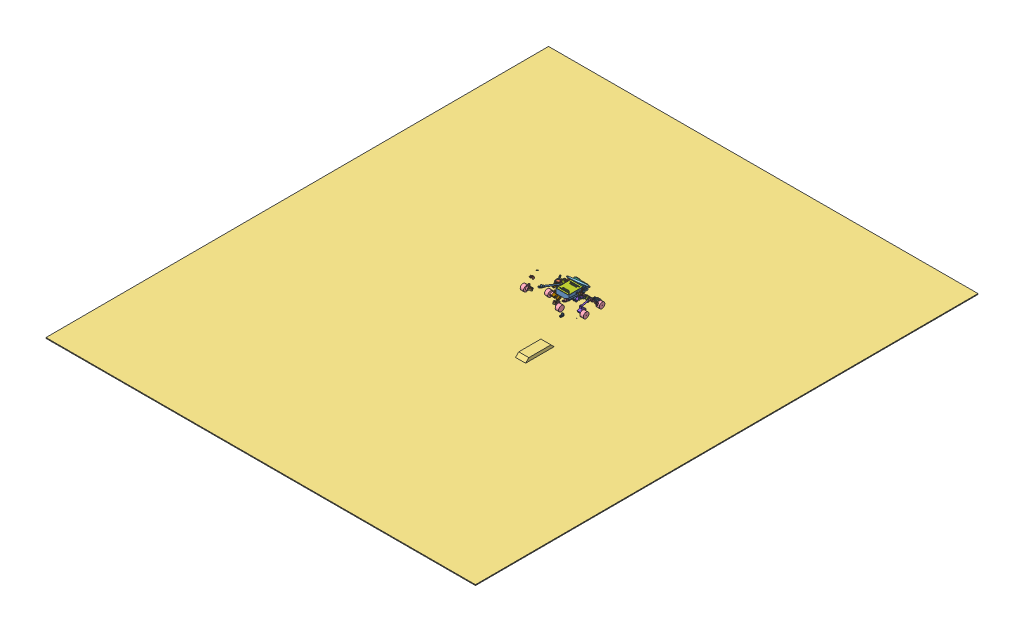
SolidWorks assembly Radius Test, configuration Default. Lengths in mm.
Overall size (5322.83 3059.19 6245.29).
49 component instances, 26 part files, 175 mates.
Components (placement in the parent):
- Electrical Box-1: Electrical Box [Default] at (-2118.9186 210.8039 -599.3636) x (0.999999 0 -0.001669) z (0.001669 0 0.999999) size (183 67.1 235)
- ROCKER JOINT LEFT VF-1: ROCKER JOINT LEFT VF [Default] at (-2135.147 239.3039 -565.7499) x (-0.001463 -0.481199 -0.87661) z (0.999999 0 -0.001669) size (91.82 74.92 47.81)
- ROCKER JOINT RIGHT-1: ROCKER JOINT RIGHT [Default] at (-2288.1468 239.3039 -565.4945) x (-0.001463 -0.481199 -0.87661) z (0.999999 0 -0.001669) size (91.82 74.92 46.81)
- Angled Motor-1: Angled Motor [Default] at (-2300.1865 333.2946 -193.9376) x (0.001463 0.481199 0.87661) z (0.000803 -0.876611 0.481199) size (22.4 36.6 70.6)
- Angled Motor-2: Angled Motor [Default] at (-2296.3187 99.9659 -773.6498) x (-0.329165 0.462199 0.823421) z (-0.86944 0.191867 -0.455259) size (22.4 36.6 70.6)
- Angled Motor-3: Angled Motor [Default] at (-1954.5271 93.2332 -721.9243) x (-0.020357 -0.06226 -0.997852) z (0.000104 -0.998059 0.062271) size (22.4 36.6 70.6)
- Angled Motor-4: Angled Motor [Default] at (-2314.8357 109.8126 -508.2919) x (-0.022203 -0.905756 -0.423217) z (-0.066951 -0.421024 0.904575) size (22.4 36.6 70.6)
- Angled Motor-5: Angled Motor [Default] at (-1934.096 105.6712 -504.4021) x (0.000717 0.90309 0.42945) z (0.001508 -0.429451 0.903089) size (22.4 36.6 70.6)
- Angled Motor-6: Angled Motor [Default] at (-1934.4209 330.8348 -199.0292) x (-0.001463 -0.481199 -0.87661) z (0.000803 -0.876611 0.481199) size (22.4 36.6 70.6)
- Bogie Pivot LEFT VF_LATEST__EVENING-1: Bogie Pivot LEFT VF_LATEST__EVENING [Default] at (-1997.0713 159.9866 -520.5028) x (-0.001666 -0.062271 -0.998058) z (0.999999 0 -0.001669) size (249.12 118.53 110.7)
- Bogie Pivot RIGHT VF_LATEST__EVENING - -1: Bogie Pivot RIGHT VF_LATEST__EVENING -  [Default] at (-2194.7174 158.3806 -518.4135) x (0.048176 -0.063499 -0.996818) z (0.997509 -0.048419 0.051294) size (249.12 118.53 161.7)
- Bogie Pivot joint VFINAL-1: Bogie Pivot joint VFINAL [Default] at (-1997.0839 210.2606 -528.0634) x (-0.001463 -0.481199 -0.87661) z (0.999999 0 -0.001669) size (160.51 100.01 61)
- Bogie - Motor mount-1: Bogie - Motor mount [Default] at (-1997.4723 161.6666 -522.5101) x (-0.001663 -0.083925 -0.996471) z (0.999999 0 -0.001669) size (251.14 245.94 117.56)
- Bogie - Motor mount - RIGHT VF-1: Bogie - Motor mount - RIGHT VF [Default] at (-2281.8294 164.2934 -524.9057) x (0.047046 -0.085126 -0.995259) z (0.997509 -0.048419 0.051294) size (251.14 245.94 117.56)
- Bogie Servo mount-1: Bogie Servo mount [Default] at (-2020.12 159.7927 -520.3812) x (-0.001666 -0.062271 -0.998058) z (0.999999 0 -0.001669) size (471.83 118.53 111.2)
- Servo_Connector_1-2: Servo_Connector_1 [Default] at (-1945.5813 363.9049 -198.0146) x (0.548168 0.402845 0.732958) z (-0.836368 0.263189 0.480854) size (40 15 40)
- Rocker Motor mount vP-2: Rocker Motor mount vP [Default] at (-1961.2668 355.4452 -196.7746) x (0.548168 0.402845 0.732958) z (-0.836368 0.263189 0.480854) size (41.99 25.29 45.95)
- ROCKER SERVO JOINT VF LEFT-1: ROCKER SERVO JOINT VF LEFT [Default] at (-1999.1852 209.1241 -533.8147) x (0.089349 -0.479211 -0.87314) z (0.996 0.043696 0.077939) size (472.67 119.9 110.7)
- ROCKER SERVO JOINT VF RIGHT-1: ROCKER SERVO JOINT VF RIGHT [Default] at (-2277.9099 209.1241 -533.3494) x (0.089349 -0.479211 -0.87314) z (0.996 0.043696 0.077939) size (474.67 119.9 110.7)
- SG90 - Micro Servo 9g - Tower Pro.4-1: SG90 - Micro Servo 9g - Tower Pro.4 [Peça] at (-2285.6539 67.6383 -751.6519) x (-0.332575 0.454133 0.826533) z (-0.365333 -0.870029 0.331032) size (34.5 3.8 16.7)
- SG90 - Micro Servo 9g - Tower Pro.4-2: SG90 - Micro Servo 9g - Tower Pro.4 [Peça] at (-2267.5431 503.5862 -287.7932) x (0.001463 0.481199 0.87661) z (0.999999 0 -0.001669) size (34.5 3.8 16.7)
- M5 BALL-1: M5 BALL [Default] at (-2003.1859 281.6004 -589.1881) x (0.000011 -0.999976 0.006877) z (0.001669 0.006877 0.999975) size (28.4 25.6 8)
- M5 BALL-2: M5 BALL [Default] at (-2236.1856 281.6004 -588.7991) x (-0.000275 0.986308 -0.164916) z (0.001646 0.164916 0.986306) size (28.4 25.6 8)
- SG90 - Micro Servo 9g - Tower Pro.4-5: SG90 - Micro Servo 9g - Tower Pro.4 [Peça] at (-1987.3147 94.1808 -721.0311) x (-0.020357 -0.06226 -0.997852) z (-0.999793 0.001164 0.020324) size (34.5 3.8 16.7)
- SG90 - Micro Servo 9g - Tower Pro.4-6: SG90 - Micro Servo 9g - Tower Pro.4 [Peça] at (-1967.3786 503.5413 -293.4557) x (-0.001463 -0.481199 -0.87661) z (-0.999999 0 0.001669) size (34.5 3.8 16.7)
- Servo_Connector_1-5: Servo_Connector_1 [Default] at (-2269.6339 78.3895 -771.0803) x (0.478238 0.095671 -0.873004) z (-0.123945 -0.976747 -0.174938) size (40 15 40)
- Rocker Motor mount vP-4: Rocker Motor mount vP [Default] at (-1981.0927 114.593 -708.9057) x (0.563873 0.051485 0.824255) z (-0.825861 0.035027 0.562784) size (41.99 25.29 45.95)
- Servo_Connector_1-6: Servo_Connector_1 [Default] at (-1965.3481 122.7464 -706.7224) x (0.563873 0.051485 0.824255) z (-0.825861 0.035027 0.562784) size (40 15 40)
- Rocker Motor mount vP-5: Rocker Motor mount vP [Default] at (-2273.3736 344.6435 -215.9314) x (-0.548168 -0.402845 -0.732958) z (0.836368 -0.263189 -0.480854) size (41.99 25.29 45.95)
- Servo_Connector_1-7: Servo_Connector_1 [Default] at (-2289.0719 350.2095 -222.3906) x (-0.548168 -0.402845 -0.732958) z (0.836368 -0.263189 -0.480854) size (40 15 40)
- Rocker P to Bogie P-1: Rocker P to Bogie P [Default] at (-2014.7332 189.2651 -617.4865) x (-0.818562 -0.386919 0.424559) z (0.001126 0.738029 0.674768) size (14.05 15.92 38.63)
- Rocker P to Bogie P-2: Rocker P to Bogie P [Default] at (-2224.7329 189.2651 -617.1359) x (0.85767 0.346253 -0.380146) z (0.001126 0.738029 0.674768) size (14.05 15.92 38.63)
- Bogie Pivot joint VFINAL-3: Bogie Pivot joint VFINAL [Default] at (-2238.4469 280.9931 -605.0242) x (-0.023795 -0.915549 -0.401503) z (-0.997509 0.048419 -0.051294) size (160.51 100.01 61)
- Bogie P to Servo M-1: Bogie P to Servo M [Default] at (-2270.4158 162.4518 -660.3391) x (0.029002 -0.381348 -0.923976) z (0.396853 -0.843999 0.360796) size (40.99 16.26 14.42)
- Bogie P to Servo M-2: Bogie P to Servo M [Default] at (-1967.3088 159.4533 -658.088) x (-0.001544 -0.380589 -0.924743) z (-0.779236 -0.579106 0.239639) size (40.99 16.26 14.42)
- R to R arm-1: R to R arm [Default] at (-2010.5512 250.7741 -535.4302) x (0.20383 0.254717 0.94529) z (-0.158588 0.961398 -0.224862) size (192.48 14 16.99)
- R to R arm-2: R to R arm [Default] at (-2228.6409 250.7741 -535.0661) x (-0.200673 0.254717 0.945965) z (0.964497 0.220592 0.145206) size (192.48 14 16.99)
- Bogie Servo mount RIGHT -5: Bogie Servo mount RIGHT  [Default] at (-2311.2472 254.39 -561.6933) x (0.326618 -0.468157 -0.821066) z (-0.370668 -0.862564 0.344367) size (471.83 118.53 104.3)
- floor-1: floor [Default] at (-1972.6087 -10 279.1439) x (-0.001669 0 -0.999999) z (0.999999 0 -0.001669) size (6236.43 50 5312.43)
- simulation wheel-1: simulation wheel [Default] at (-1881.921 330.8348 -199.1169) x (-0.000505 -0.953126 -0.302573) z (-0.999999 0 0.001669) size (70 70 42)
- simulation wheel-2: simulation wheel [Default] at (-1944.0293 93.221 -722.1377) x (0.00967 0.905698 0.423814) z (0.999793 -0.001164 -0.020324) size (70 70 42)
- simulation wheel-3: simulation wheel [Default] at (-1923.596 105.6712 -504.4196) x (-0.000671 -0.915639 -0.402002) z (0.999999 0 -0.001669) size (70 70 42)
- simulation wheel-4: simulation wheel [Default] at (-2292.4504 109.0565 -777.2061) x (-0.656396 -0.015758 -0.754252) z (0.368408 0.865771 -0.338698) size (70 70 42)
- simulation wheel-5: simulation wheel [Default] at (-2325.3095 110.321 -508.8305) x (-0.016438 -0.866737 -0.498495) z (-0.997509 0.048419 -0.051294) size (70 70 42)
- simulation wheel-6: simulation wheel [Default] at (-2310.6864 333.2946 -193.9201) x (0.000225 -0.990877 0.134766) z (-0.999999 0 0.001669) size (70 70 42)
- Differential-2: Differential [Default] at (-2119.7824 273.8039 -646.8547) x (0.993317 0 -0.115422) z (0.115422 0 0.993317) size (260.8 54.75 29)
- lid back-1: lid back [Default] at (-2119.3943 269.2693 -628.2763) x (0.999999 0 -0.001669) z (0.001669 0 0.999999) size (154.34 2.57 55)
- Lid front-1: Lid front [Default] at (-2115.5606 270.2501 -448.2824) x (0.999999 0 -0.001669) z (0.001669 0 0.999999) size (154.34 2.57 180)
- Rocker Motor mount vP - Back-1: Rocker Motor mount vP - Back [Default] at (-2283.3205 67.6413 -767.0441) x (0.478238 0.095671 -0.873004) z (-0.123945 -0.976747 -0.174938) size (41.36 25.29 44.88)
Mates (geometry in assembly coordinates):
- Concentric4: concentric anti-aligned: cylinder of Electrical Box-1 through (-2043.1471 239.3039 -565.9035) axis (0.999999 0 -0.001669) radius 5.5; cylinder of ROCKER JOINT LEFT VF-1 through (-2018.5 239.3039 -565.9446) axis (-0.999999 0 0.001669) radius 4.825
- Concentric8: concentric anti-aligned: cylinder of Electrical Box-1 through (-2196.1469 239.3039 -565.6481) axis (-0.999999 0 0.001669) radius 5.5; cylinder of ROCKER JOINT RIGHT-1 through (-2209.1469 239.3039 -565.6264) axis (0.999999 0 -0.001669) radius 4.825
- Coincident7: coincident anti-aligned: plane of ROCKER JOINT LEFT VF-1 through (-2012.1472 239.3039 -565.9552) normal (0.999999 0 -0.001669); plane of M5 BALL-1 through (-2012.1859 281.6004 -589.1731) normal (-0.999999 0 0.001669)
- Concentric9: concentric aligned: cylinder of ROCKER JOINT LEFT VF-1 through (-2043.1869 281.6004 -589.1213) axis (0.999999 0 -0.001669) radius 2.5; cylinder of M5 BALL-1 through (-2022.3859 281.6004 -589.156) axis (0.999999 0 -0.001669) radius 2.5
- Concentric10: concentric aligned: cylinder of ROCKER JOINT RIGHT-1 through (-2196.1847 281.6004 -588.8659) axis (-0.999999 0 0.001669) radius 2.5; cylinder of M5 BALL-2 through (-2216.9856 281.6004 -588.8312) axis (-0.999999 0 0.001669) radius 2.5
- Coincident10: coincident anti-aligned: plane of ROCKER JOINT RIGHT-1 through (-2227.1469 239.3039 -565.5963) normal (-0.999999 0 0.001669); plane of M5 BALL-2 through (-2227.1856 281.6004 -588.8142) normal (0.999999 0 -0.001669)
- Coincident17: coincident anti-aligned: plane of Servo_Connector_1-2 through (-1967.2329 344.5675 -206.1901) normal (0.000803 -0.876611 0.481199); plane of Rocker Motor mount vP-2 through (-1967.2329 344.5675 -206.1901) normal (-0.000803 0.876611 -0.481199)
- Coincident18: coincident anti-aligned: plane of Servo_Connector_1-2 through (-1972.2296 345.6743 -204.1656) normal (-0.999999 0 0.001669); plane of Rocker Motor mount vP-2 through (-1972.2296 345.6716 -204.1705) normal (0.999999 0 -0.001669)
- Concentric15: concentric anti-aligned: cylinder of Servo_Connector_1-2 through (-1981.695 357.7167 -213.384) axis (0.000803 -0.876611 0.481199) radius 1; cylinder of Rocker Motor mount vP-2 through (-1981.6749 335.8014 -201.354) axis (-0.000803 0.876611 -0.481199) radius 1
- Concentric16: concentric anti-aligned: cylinder of Servo_Connector_1-2 through (-1952.795 357.7167 -213.4322) axis (0.000803 -0.876611 0.481199) radius 1; cylinder of Rocker Motor mount vP-2 through (-1952.7749 335.8014 -201.4023) axis (-0.000803 0.876611 -0.481199) radius 1
- Concentric18: concentric anti-aligned: cylinder of Rocker Motor mount vP-3 through (-694.0736 119.6172 -1166.1027) axis (0.000091 0.995626 -0.093423) radius 1; cylinder of Servo_Connector_1-5 through (-2286.5678 54.103 -744.5828) axis (-0.86944 0.191867 -0.455259) radius 1
- Concentric19: concentric anti-aligned: cylinder of Rocker Motor mount vP-3 through (-718.2037 121.1052 -1150.2681) axis (0.000091 0.995626 -0.093423) radius 1; cylinder of Servo_Connector_1-5 through (-2276.0097 79.2469 -754.1496) axis (-0.86944 0.191867 -0.455259) radius 1
- Coincident20: coincident anti-aligned: plane of Rocker Motor mount vP-3 through (-703.2257 129.8812 -1163.7666) normal (-0.834952 0.051489 0.547909); plane of Servo_Connector_1-5 through (-2295.3921 64.1583 -756.4409) normal (-0.365333 -0.870029 0.331032)
- Coincident21: coincident anti-aligned: plane of Rocker Motor mount vP-3 through (-706.1378 130.3175 -1159.1197) normal (0.000091 0.995626 -0.093423); plane of Servo_Connector_1-5 through (-2294.3303 69.553 -756.1951) normal (-0.86944 0.191867 -0.455259)
- Concentric20: concentric anti-aligned: cylinder of Rocker Motor mount vP-4 through (-2001.7621 98.8056 -721.0249) axis (-0.000104 0.998059 -0.062271) radius 1; cylinder of Servo_Connector_1-6 through (-2001.7647 123.7571 -722.5816) axis (0.000104 -0.998059 0.062271) radius 1
- Concentric21: concentric anti-aligned: cylinder of Rocker Motor mount vP-4 through (-1972.8681 98.7719 -721.6123) axis (-0.000104 0.998059 -0.062271) radius 1; cylinder of Servo_Connector_1-6 through (-1972.8707 123.7234 -723.169) axis (0.000104 -0.998059 0.062271) radius 1
- Coincident22: coincident anti-aligned: plane of Rocker Motor mount vP-4 through (-1992.2684 108.918 -719.5502) normal (0.999793 -0.001164 -0.020324); plane of Servo_Connector_1-6 through (-1992.2683 108.9184 -719.5446) normal (-0.999793 0.001164 0.020324)
- Coincident23: coincident anti-aligned: plane of Rocker Motor mount vP-4 through (-1987.3162 108.7694 -721.9413) normal (-0.000104 0.998059 -0.062271); plane of Servo_Connector_1-6 through (-1987.3162 108.7694 -721.9413) normal (0.000104 -0.998059 0.062271)
- Concentric22: concentric anti-aligned: cylinder of Rocker Motor mount vP-5 through (-2252.9414 337.989 -196.916) axis (-0.000803 0.876611 -0.481199) radius 1; cylinder of Servo_Connector_1-7 through (-2252.9614 359.9042 -208.946) axis (0.000803 -0.876611 0.481199) radius 1
- Concentric23: concentric anti-aligned: cylinder of Rocker Motor mount vP-5 through (-2281.8413 337.989 -196.8678) axis (-0.000803 0.876611 -0.481199) radius 1; cylinder of Servo_Connector_1-7 through (-2281.8614 359.9042 -208.8977) axis (0.000803 -0.876611 0.481199) radius 1
- Coincident24: coincident anti-aligned: plane of Rocker Motor mount vP-5 through (-2262.4027 345.651 -203.7235) normal (-0.999999 0 0.001669); plane of Servo_Connector_1-7 through (-2262.4027 345.6483 -203.7284) normal (0.999999 0 -0.001669)
- Coincident25: coincident anti-aligned: plane of Rocker Motor mount vP-5 through (-2267.3994 346.7551 -201.7039) normal (-0.000803 0.876611 -0.481199); plane of Servo_Connector_1-7 through (-2267.3994 346.7551 -201.7039) normal (0.000803 -0.876611 0.481199)
- Concentric25: concentric anti-aligned: cylinder of Servo_Connector_1-2 through (-1967.2418 354.2102 -211.4833) axis (-0.000803 0.876611 -0.481199) radius 1.05; cylinder of SG90 - Micro Servo 9g - Tower Pro.4-6 through (-1967.3786 503.5413 -293.4557) axis (0.000803 -0.876611 0.481199) radius 2.3
- Coincident31: coincident anti-aligned: plane of Servo_Connector_1-2 through (-1971.9418 364.5359 -200.9775) normal (0.996235 0.042416 0.075607); plane of SG90 - Micro Servo 9g - Tower Pro.4-6 through (-1969.4119 513.7777 -318.038) normal (-0.996235 -0.042416 -0.075607)
- Coincident33: coincident anti-aligned: plane of Angled Motor-6 through (-1943.7209 330.8348 -199.0137) normal (-0.999999 0 0.001669); plane of Rocker Motor mount vP-2 through (-1943.7172 355.4452 -196.8039) normal (0.999999 0 -0.001669)
- Parallel4: parallel aligned: line of Angled Motor-6 through (-1925.1316 319.1337 -205.3982) axis (-0.000803 0.876611 -0.481199); line of Rocker Motor mount vP-2 through (-1943.7417 330.2758 -211.4833) axis (-0.000803 0.876611 -0.481199)
- Coincident36: coincident aligned: line of Angled Motor-6 through (-1943.758 348.0619 -221.2467) axis (0.001463 0.481199 0.87661); line of Rocker Motor mount vP-2 through (-1943.758 348.0619 -221.2467) axis (0.001463 0.481199 0.87661)
- Coincident37: coincident anti-aligned: line of Angled Motor-6 through (-1943.758 348.0619 -221.2467) axis (0.000803 -0.876611 0.481199); line of Rocker Motor mount vP-2 through (-1943.7417 330.2758 -211.4833) axis (-0.000803 0.876611 -0.481199)
- Coincident38: coincident anti-aligned: plane of SG90 - Micro Servo 9g - Tower Pro.4-2 through (-2265.5433 529.8237 -283.2326) normal (0.996235 0.042416 0.075607); plane of Servo_Connector_1-7 through (-2262.7147 353.085 -221.3525) normal (-0.996235 -0.042416 -0.075607)
- Concentric26: concentric anti-aligned: circle of SG90 - Micro Servo 9g - Tower Pro.4-2; cylinder of Servo_Connector_1-7 through (-2267.4082 356.3978 -206.9971) axis (-0.000803 0.876611 -0.481199) radius 1.05
- Coincident42: coincident aligned: line of Angled Motor-1 through (-2290.9236 350.5217 -216.1861) axis (0.000803 -0.876611 0.481199); line of Rocker Motor mount vP-5 through (-2290.9236 350.5217 -216.1861) axis (0.000803 -0.876611 0.481199)
- Coincident43: coincident anti-aligned: line of Angled Motor-1 through (-2290.8908 361.3006 -196.55) axis (0.000803 -0.876611 0.481199); line of Rocker Motor mount vP-5 through (-2290.8745 343.5145 -186.7867) axis (-0.000803 0.876611 -0.481199)
- Coincident44: coincident aligned: line of Angled Motor-1 through (-2290.8908 361.3006 -196.55) axis (-0.001463 -0.481199 -0.87661); line of Rocker Motor mount vP-5 through (-2290.8908 361.3006 -196.55) axis (-0.001463 -0.481199 -0.87661)
- Coincident45: coincident anti-aligned: plane of Angled Motor-1 through (-2290.8865 333.2946 -193.9531) normal (0.999999 0 -0.001669); plane of Rocker Motor mount vP-5 through (-2290.9231 344.6435 -215.9021) normal (-0.999999 0 0.001669)
- Coincident46: coincident anti-aligned: plane of Angled Motor-4 through (-2305.5588 109.3623 -507.8149) normal (0.997509 -0.048419 0.051294); plane of Bogie - Motor mount - RIGHT VF-1 through (-2301.9132 165.2683 -525.9385) normal (-0.997509 0.048419 -0.051294)
- Concentric32: concentric aligned: circle of Angled Motor-4; cylinder of Bogie - Motor mount - RIGHT VF-1 through (-2268.5612 107.5664 -505.9124) axis (-0.997509 0.048419 -0.051294) radius 3.9367
- Parallel10: parallel aligned: line of Angled Motor-4 through (-2306.2896 96.1865 -506.042) axis (0.066951 0.421024 -0.904575); line of Bogie - Motor mount - RIGHT VF-1 through (-2306.338 95.9638 -505.311) axis (0.066951 0.421024 -0.904575)
- Coincident58: coincident anti-aligned: plane of Angled Motor-5 through (-1943.396 105.6712 -504.3865) normal (-0.999999 0 0.001669); plane of Bogie - Motor mount-1 through (-1943.4264 161.6666 -522.6003) normal (0.999999 0 -0.001669)
- Concentric33: concentric aligned: circle of Angled Motor-5; cylinder of Bogie - Motor mount-1 through (-1980.4859 105.6712 -504.3246) axis (0.999999 0 -0.001669) radius 3.9367
- Parallel11: parallel anti-aligned: line of Angled Motor-5 through (-1943.3771 112.6937 -493.0744) axis (-0.001508 0.429451 -0.903089); line of Bogie - Motor mount-1 through (-1943.4549 134.7556 -539.6491) axis (0.001508 -0.429451 0.903089)
- Concentric34: concentric anti-aligned: cylinder of Bogie Pivot LEFT VF_LATEST__EVENING-1 through (-2024.2653 168.2069 -636.7238) axis (0.999999 0 -0.001669) radius 4.75; cylinder of Bogie Pivot joint VFINAL-1 through (-1979.709 168.2069 -636.7982) axis (-0.999999 0 0.001669) radius 5.5
- Coincident70: coincident anti-aligned: plane of ROCKER JOINT LEFT VF-1 through (-2014.6897 217.7751 -591.4202) normal (-0.001126 -0.738029 -0.674768); plane of Rocker P to Bogie P-1 through (-2014.6897 217.7751 -591.4202) normal (0.001126 0.738029 0.674768)
- Coincident71: coincident anti-aligned: plane of ROCKER JOINT LEFT VF-1 through (-2014.7455 196.0128 -624.8668) normal (0.001232 -0.674769 0.738028); plane of Rocker P to Bogie P-1 through (-2014.7455 196.0128 -624.8668) normal (-0.001232 0.674769 -0.738028)
- Coincident72: coincident anti-aligned: plane of ROCKER JOINT LEFT VF-1 through (-2015.9659 205.6629 -598.4272) normal (0.999999 0 -0.001669); plane of Rocker P to Bogie P-1 through (-2015.9659 205.6629 -598.4272) normal (-0.999999 0 0.001669)
- Coincident73: coincident anti-aligned: plane of Bogie Pivot joint VFINAL-1 through (-2014.7332 189.2651 -617.4865) normal (0.001126 0.738029 0.674768); plane of Rocker P to Bogie P-1 through (-2014.7332 189.2651 -617.4865) normal (-0.001126 -0.738029 -0.674768)
- Coincident74: coincident anti-aligned: plane of Bogie Pivot joint VFINAL-1 through (-2015.9941 187.2408 -615.2703) normal (0.999999 0 -0.001669); plane of Rocker P to Bogie P-1 through (-2015.9941 187.2408 -615.2703) normal (-0.999999 0 0.001669)
- Coincident75: coincident anti-aligned: plane of Bogie Pivot joint VFINAL-1 through (-2014.7455 196.0128 -624.8668) normal (0.001232 -0.674769 0.738028); plane of Rocker P to Bogie P-1 through (-2014.7455 196.0128 -624.8668) normal (-0.001232 0.674769 -0.738028)
- Coincident76: coincident anti-aligned: plane of Bogie Pivot LEFT VF_LATEST__EVENING-1 through (-1968.268 163.8885 -614.2262) normal (0.00164 -0.185423 0.982657); plane of Bogie - Motor mount-1 through (-1968.268 163.8885 -614.2262) normal (-0.00164 0.185423 -0.982657)
- Coincident77: coincident anti-aligned: plane of Bogie Pivot LEFT VF_LATEST__EVENING-1 through (-1970.1221 173.7151 -612.3689) normal (-0.00031 -0.982659 -0.185423); plane of Bogie - Motor mount-1 through (-1997.4738 156.9362 -523.4027) normal (0.00031 0.982659 0.185423)
- Coincident78: coincident anti-aligned: plane of Bogie Pivot LEFT VF_LATEST__EVENING-1 through (-1966.9495 173.7151 -612.3742) normal (-0.999999 0 0.001669); plane of Bogie - Motor mount-1 through (-1966.9535 160.9405 -614.7847) normal (0.999999 0 -0.001669)
- Coincident79: coincident anti-aligned: plane of ROCKER JOINT RIGHT-1 through (-2224.6894 217.7751 -591.0696) normal (-0.001126 -0.738029 -0.674768); plane of Rocker P to Bogie P-2 through (-2224.6894 217.7751 -591.0696) normal (0.001126 0.738029 0.674768)
- Coincident84: coincident anti-aligned: plane of Rocker P to Bogie P-2 through (-2224.7329 189.2651 -617.1359) normal (-0.001126 -0.738029 -0.674768); plane of Bogie Pivot joint VFINAL-3 through (-2224.7329 189.2651 -617.1359) normal (0.001126 0.738029 0.674768)
- Coincident85: coincident anti-aligned: plane of Rocker P to Bogie P-2 through (-2225.4382 182.5348 -609.7735) normal (-0.070528 -0.67303 0.736245); plane of Bogie Pivot joint VFINAL-3 through (-2225.4382 182.5348 -609.7735) normal (0.070528 0.67303 -0.736245)
- Coincident86: coincident anti-aligned: plane of Rocker P to Bogie P-2 through (-2226.1256 191.362 -619.4272) normal (-0.997509 0.048419 -0.051294); plane of Bogie Pivot joint VFINAL-3 through (-2226.1256 191.362 -619.4272) normal (0.997509 -0.048419 0.051294)
- Concentric38: concentric aligned: cylinder of Bogie Pivot RIGHT VF_LATEST__EVENING - -1 through (-2266.3035 170.2232 -638.5251) axis (0.997509 -0.048419 0.051294) radius 4.75; cylinder of Bogie Pivot joint VFINAL-3 through (-2259.7341 169.9043 -638.1873) axis (0.997509 -0.048419 0.051294) radius 5.5
- Concentric41: concentric aligned: cylinder of Bogie Pivot RIGHT VF_LATEST__EVENING - -1 through (-2266.3035 170.2232 -638.5251) axis (0.997509 -0.048419 0.051294) radius 4.75; cylinder of Bogie Pivot joint VFINAL-3 through (-2259.7341 169.9043 -638.1873) axis (0.997509 -0.048419 0.051294) radius 5.5
- Coincident89: coincident anti-aligned: plane of Bogie Pivot RIGHT VF_LATEST__EVENING - -1 through (-2275.212 156.4694 -618.2005) normal (0.038072 0.981747 0.186341); plane of Bogie - Motor mount - RIGHT VF-1 through (-2282.7741 139.9324 -529.5296) normal (-0.038072 -0.981747 -0.186341)
- Coincident91: coincident anti-aligned: plane of Bogie Pivot RIGHT VF_LATEST__EVENING - -1 through (-2272.4768 166.1726 -616.216) normal (-0.05938 -0.183924 0.981145); plane of Bogie - Motor mount - RIGHT VF-1 through (-2272.4768 166.1726 -616.216) normal (0.05938 0.183924 -0.981145)
- Coincident93: coincident anti-aligned: plane of Bogie Pivot RIGHT VF_LATEST__EVENING - -1 through (-2275.212 156.4694 -618.2005) normal (0.997509 -0.048419 0.051294); plane of Bogie - Motor mount - RIGHT VF-1 through (-2274.717 169.2321 -615.7781) normal (-0.997509 0.048419 -0.051294)
- Coincident94: coincident anti-aligned: plane of Bogie Pivot RIGHT VF_LATEST__EVENING - -1 through (-2270.6305 161.6946 -660.0334) normal (0.029002 -0.381348 -0.923976); plane of Bogie P to Servo M-1 through (-2270.4158 162.4518 -660.3391) normal (-0.029002 0.381348 0.923976)
- Coincident95: coincident anti-aligned: plane of Bogie Pivot RIGHT VF_LATEST__EVENING - -1 through (-2279.6597 166.1255 -662.1455) normal (-0.265121 -0.894193 0.360734); plane of Bogie P to Servo M-1 through (-2266.7148 157.6095 -673.7413) normal (0.265121 0.894193 -0.360734)
- Coincident96: coincident anti-aligned: plane of Bogie Pivot RIGHT VF_LATEST__EVENING - -1 through (-2280.6713 162.7136 -660.7691) normal (0.963779 -0.234503 0.127036); plane of Bogie P to Servo M-1 through (-2280.0536 164.7968 -661.6095) normal (-0.963779 0.234503 -0.127036)
- Coincident97: coincident anti-aligned: plane of Bogie Pivot LEFT VF_LATEST__EVENING-1 through (-1968.1522 159.4533 -658.0866) normal (-0.001544 -0.380589 -0.924743); plane of Bogie P to Servo M-2 through (-1967.3088 159.4533 -658.088) normal (0.001544 0.380589 0.924743)
- Coincident98: coincident anti-aligned: plane of Bogie Pivot LEFT VF_LATEST__EVENING-1 through (-1965.8286 168.7007 -661.8964) normal (0.000635 -0.924744 0.380588); plane of Bogie P to Servo M-2 through (-1967.3151 168.7007 -661.8939) normal (-0.000635 0.924744 -0.380588)
- Coincident99: coincident anti-aligned: plane of Bogie Pivot LEFT VF_LATEST__EVENING-1 through (-1969.6448 168.7007 -661.89) normal (0.999999 0 -0.001669); plane of Bogie P to Servo M-2 through (-1969.6586 151.2225 -670.2006) normal (-0.999999 0 0.001669)
- Coincident100: coincident anti-aligned: plane of ROCKER JOINT LEFT VF-1 through (-2010.5512 250.7741 -535.4302) normal (0.20383 0.254717 0.94529); plane of R to R arm-1 through (-2010.5512 250.7741 -535.4302) normal (-0.20383 -0.254717 -0.94529)
- Coincident101: coincident anti-aligned: plane of ROCKER JOINT LEFT VF-1 through (-2010.5468 241.1183 -532.8293) normal (-0.000434 0.965584 -0.260092); plane of R to R arm-1 through (-2010.5468 241.1183 -532.8293) normal (0.000434 -0.965584 0.260092)
- Coincident102: coincident anti-aligned: plane of ROCKER JOINT LEFT VF-1 through (-2009.8313 253.6321 -536.3555) normal (-0.979006 0.052604 0.196925); plane of R to R arm-1 through (-2009.8313 253.6321 -536.3555) normal (0.979006 -0.052604 -0.196925)
- Coincident103: coincident anti-aligned: plane of ROCKER JOINT RIGHT-1 through (-2228.6409 250.7741 -535.0661) normal (-0.200673 0.254717 0.945965); plane of R to R arm-2 through (-2228.6409 250.7741 -535.0661) normal (0.200673 -0.254717 -0.945965)
- Coincident106: coincident anti-aligned: plane of ROCKER SERVO JOINT VF RIGHT-1 through (-2267.2664 299.802 -352.9868) normal (0.200673 -0.254717 -0.945965); plane of R to R arm-2 through (-2277.0929 301.3297 -355.4827) normal (-0.200673 0.254717 0.945965)
- Coincident107: coincident anti-aligned: plane of ROCKER SERVO JOINT VF RIGHT-1 through (-2238.4366 250.1182 -536.9675) normal (0.979564 0.065591 0.190139); plane of R to R arm-2 through (-2238.4366 250.1182 -536.9675) normal (-0.979564 -0.065591 -0.190139)
- Coincident108: coincident anti-aligned: plane of ROCKER SERVO JOINT VF RIGHT-1 through (-2277.0929 301.3297 -355.4827) normal (0.013615 -0.964789 0.262674); plane of R to R arm-2 through (-2277.0929 301.3297 -355.4827) normal (-0.013615 0.964789 -0.262674)
- Coincident109: coincident anti-aligned: plane of ROCKER SERVO JOINT VF LEFT-1 through (-1971.318 299.802 -353.4808) normal (-0.20383 -0.254717 -0.94529); plane of R to R arm-1 through (-1973.5295 290.2653 -350.4342) normal (0.20383 0.254717 0.94529)
- Coincident110: coincident anti-aligned: plane of ROCKER SERVO JOINT VF LEFT-1 through (-2010.5468 241.1183 -532.8293) normal (-0.000434 0.965584 -0.260092); plane of R to R arm-1 through (-2010.5468 241.1183 -532.8293) normal (0.000434 -0.965584 0.260092)
- Coincident111: coincident anti-aligned: plane of ROCKER SERVO JOINT VF LEFT-1 through (-1973.5295 290.2653 -350.4342) normal (0.979006 -0.052604 -0.196925); plane of R to R arm-1 through (-1973.5295 290.2653 -350.4342) normal (-0.979006 0.052604 0.196925)
- Coincident112: coincident anti-aligned: plane of Angled Motor-3 through (-1963.8252 93.2441 -721.7353) normal (-0.999793 0.001164 0.020324); plane of Rocker Motor mount vP-4 through (-1963.5468 114.5726 -709.2624) normal (0.999793 -0.001164 -0.020324)
- Coincident113: coincident aligned: line of Angled Motor-3 through (-1964.0559 118.2967 -734.5178) axis (0.020357 0.06226 0.997852); line of Rocker Motor mount vP-4 through (-1964.0559 118.2967 -734.5178) axis (0.020357 0.06226 0.997852)
- Coincident114: coincident anti-aligned: line of Angled Motor-3 through (-1964.0559 118.2967 -734.5178) axis (0.000104 -0.998059 0.062271); line of Rocker Motor mount vP-4 through (-1964.0538 98.0465 -733.2544) axis (-0.000104 0.998059 -0.062271)
- Concentric44: concentric anti-aligned: cylinder of SG90 - Micro Servo 9g - Tower Pro.4-5 through (-1987.3147 94.1808 -721.0311) axis (0.000104 -0.998059 0.062271) radius 2.3; cylinder of Servo_Connector_1-6 through (-1987.3173 119.748 -722.6262) axis (-0.000104 0.998059 -0.062271) radius 1.05
- Coincident118: coincident anti-aligned: plane of SG90 - Micro Servo 9g - Tower Pro.4-5 through (-1993.8039 112.561 -723.9496) normal (-0.020357 -0.06226 -0.997852); plane of Servo_Connector_1-6 through (-1965.7229 123.5968 -725.211) normal (0.020357 0.06226 0.997852)
- Coincident122: coincident anti-aligned: plane of Bogie Servo mount-1 through (-1968.2158 143.853 -695.9918) normal (0.001544 0.380589 0.924743); plane of Bogie P to Servo M-2 through (-1967.3721 143.853 -695.9933) normal (-0.001544 -0.380589 -0.924743)
- Coincident123: coincident anti-aligned: plane of Bogie Servo mount-1 through (-1968.2221 153.1004 -699.7977) normal (0.000635 -0.924744 0.380588); plane of Bogie P to Servo M-2 through (-1967.3151 168.7007 -661.8939) normal (-0.000635 0.924744 -0.380588)
- Coincident124: coincident anti-aligned: plane of Bogie Servo mount-1 through (-1969.6776 146.5353 -681.5893) normal (0.999999 0 -0.001669); plane of Bogie P to Servo M-2 through (-1969.6998 141.0787 -694.8476) normal (-0.999999 0 0.001669)
- Concentric52: concentric anti-aligned: circle of SG90 - Micro Servo 9g - Tower Pro.4-1; cylinder of Servo_Connector_1-5 through (-2284.7665 67.4424 -751.1872) axis (0.86944 -0.191867 0.455259) radius 1.05
- Coincident144: coincident anti-aligned: plane of SG90 - Micro Servo 9g - Tower Pro.4-1 through (-2284.6702 64.0609 -751.9632) normal (-0.346643 -0.893511 0.285442); plane of Servo_Connector_1-5 through (-2276.0313 57.0334 -763.4699) normal (0.346643 0.893511 -0.285442)
- Coincident150: coincident anti-aligned: plane of Angled Motor-2 through (-2299.7449 91.9142 -770.4999) normal (-0.368408 -0.865771 0.338698); plane of Rocker Motor mount vP-3 through (-733.1863 135.4535 -1157.9309) normal (-0.834952 0.051489 0.547909)
- Coincident162: coincident anti-aligned: plane of Bogie P to Servo M-1 through (-2269.2271 146.8203 -698.2129) normal (0.029002 -0.381348 -0.923976); plane of Bogie Servo mount RIGHT -5 through (-2269.2271 146.8203 -698.2129) normal (-0.029002 0.381348 0.923976)
- Concentric71: concentric anti-aligned: circle of Angled Motor-6; cylinder of simulation wheel-1 through (-1923.921 330.8348 -199.0468) axis (0.999999 0 -0.001669) radius 2.5
- Coincident173: coincident anti-aligned: plane of Angled Motor-6 through (-1923.921 330.8348 -199.0468) normal (0.999999 0 -0.001669); plane of simulation wheel-1 through (-1923.921 330.8348 -199.0468) normal (-0.999999 0 0.001669)
- Coincident174: coincident anti-aligned: plane of Angled Motor-5 through (-1923.596 105.6712 -504.4196) normal (0.999999 0 -0.001669); plane of simulation wheel-3 through (-1923.596 105.6712 -504.4196) normal (-0.999999 0 0.001669)
- Concentric72: concentric anti-aligned: circle of Angled Motor-5; cylinder of simulation wheel-3 through (-1881.5961 105.6712 -504.4897) axis (-0.999999 0 0.001669) radius 2.5
- Coincident175: coincident anti-aligned: plane of Angled Motor-3 through (-1944.0293 93.221 -722.1377) normal (0.999793 -0.001164 -0.020324); plane of simulation wheel-2 through (-1944.0293 93.221 -722.1377) normal (-0.999793 0.001164 0.020324)
- Concentric73: concentric aligned: circle of Angled Motor-3; cylinder of simulation wheel-2 through (-1902.038 93.1721 -722.9913) axis (-0.999793 0.001164 0.020324) radius 2.5
- Coincident176: coincident anti-aligned: plane of Angled Motor-2 through (-2292.4504 109.0565 -777.2061) normal (0.368408 0.865771 -0.338698); plane of simulation wheel-4 through (-2292.4504 109.0565 -777.2061) normal (-0.368408 -0.865771 0.338698)
- Concentric74: concentric aligned: circle of Angled Motor-2; cylinder of simulation wheel-4 through (-2276.9773 145.4189 -791.4315) axis (-0.368408 -0.865771 0.338698) radius 2.5
- Coincident177: coincident anti-aligned: plane of Angled Motor-4 through (-2325.3095 110.321 -508.8305) normal (-0.997509 0.048419 -0.051294); plane of simulation wheel-5 through (-2325.3095 110.321 -508.8305) normal (0.997509 -0.048419 0.051294)
- Concentric75: concentric anti-aligned: circle of Angled Motor-4; cylinder of simulation wheel-5 through (-2367.2049 112.3546 -510.9848) axis (0.997509 -0.048419 0.051294) radius 2.5
- Coincident178: coincident anti-aligned: plane of Angled Motor-1 through (-2310.6864 333.2946 -193.9201) normal (-0.999999 0 0.001669); plane of simulation wheel-6 through (-2310.6864 333.2946 -193.9201) normal (0.999999 0 -0.001669)
- Concentric76: concentric aligned: circle of Angled Motor-1; cylinder of simulation wheel-6 through (-2352.6864 333.2946 -193.85) axis (0.999999 0 -0.001669) radius 2.5
- Lock5: lock: unknown of ROCKER SERVO JOINT VF LEFT-1; unknown of SG90 - Micro Servo 9g - Tower Pro.4-6
- Lock6: lock: unknown of ROCKER SERVO JOINT VF RIGHT-1; unknown of SG90 - Micro Servo 9g - Tower Pro.4-2
- Lock2: lock: unknown of SG90 - Micro Servo 9g - Tower Pro.4-1; unknown of Bogie Servo mount RIGHT -5
- Lock3: lock: unknown of Bogie Servo mount-1; unknown of SG90 - Micro Servo 9g - Tower Pro.4-5
- Distance1: distance = 1.8 mm anti-aligned: plane of Servo_Connector_1-2 through (-1945.5829 365.6582 -198.977) normal (-0.000803 0.876611 -0.481199); plane of ROCKER SERVO JOINT VF LEFT-1 through (-1979.9013 292.2731 -336.3477) normal (0.000803 -0.876611 0.481199)
- Distance2: distance = 1.8 mm anti-aligned: plane of ROCKER SERVO JOINT VF RIGHT-1 through (-2258.626 292.2731 -335.8825) normal (0.000803 -0.876611 0.481199); plane of Servo_Connector_1-7 through (-2289.0735 351.9627 -223.3529) normal (-0.000803 0.876611 -0.481199)
- Distance4: distance = 1.8 mm anti-aligned: plane of Servo_Connector_1-6 through (-1965.3483 124.7426 -706.847) normal (-0.000104 0.998059 -0.062271); plane of Bogie Servo mount-1 through (-1979.2914 124.394 -741.3162) normal (0.000104 -0.998059 0.062271)
- Distance5: distance = 8 mm anti-aligned: plane of Bogie Pivot joint VFINAL-3 through (-2240.4419 281.0899 -605.1268) normal (-0.997509 0.048419 -0.051294); plane of Bogie Pivot RIGHT VF_LATEST__EVENING - -1 through (-2252.1965 169.5384 -637.7997) normal (0.997509 -0.048419 0.051294)
- Distance6: distance = 8 mm anti-aligned: plane of Bogie Pivot joint VFINAL-1 through (-1995.0839 210.2606 -528.0668) normal (0.999999 0 -0.001669); plane of Bogie Pivot LEFT VF_LATEST__EVENING-1 through (-1987.2654 168.2069 -636.7856) normal (-0.999999 0 0.001669)
- Distance8: distance = 8 mm anti-aligned: plane of ROCKER JOINT LEFT VF-1 through (-2032.1471 239.3039 -565.9218) normal (-0.999999 0 0.001669); plane of Electrical Box-1 through (-2040.3433 207.8039 -683.4083) normal (0.999999 0 -0.001669)
- Distance9: distance = 8 mm anti-aligned: plane of ROCKER JOINT RIGHT-1 through (-2207.1469 239.3039 -565.6297) normal (0.999999 0 -0.001669); plane of Electrical Box-1 through (-2199.3431 207.8039 -683.1429) normal (-0.999999 0 0.001669)
- Concentric81: concentric anti-aligned: cylinder of Electrical Box-1 through (-2119.0348 188.0981 -648.4902) axis (0 1 0) radius 5.5; cylinder of Differential-2 through (-2119.0348 264.4065 -648.4902) axis (0 -1 0) radius 4.825
- Coincident208: coincident anti-aligned: plane of Electrical Box-1 through (-2118.1711 256.6545 -600.9991) normal (0 1 0); plane of Differential-2 through (-2119.0348 256.6545 -648.4902) normal (0 -1 0)
- Parallel51: parallel: plane of Electrical Box-1 through (-2146.2064 252.3667 -1000.9539) normal (0.000004 0.99999 -0.00439); plane of ROCKER JOINT LEFT VF-1 through (-2044.531 274.2969 -959.8638) normal (0.000004 0.99999 -0.00439)
- Parallel53: parallel: plane of Electrical Box-1 through (-2146.2064 252.3667 -1000.9539) normal (0.000004 0.99999 -0.00439); plane of ROCKER JOINT RIGHT-1 through (-2249.5309 274.2969 -960.0642) normal (0.000004 0.99999 -0.00439)
- Coincident218: coincident anti-aligned: plane of Electrical Box-1 through (-2070.4627 252.2398 -1029.7931) normal (-0.939694 -0.342017 0.000583); plane of Lid front-1 through (-2070.3406 251.9043 -1029.7915) normal (0.939694 0.342017 -0.000583)
- Coincident219: coincident anti-aligned: plane of Electrical Box-1 through (-2146.1784 192.2404 -1029.6036) normal (-0.000977 0.00439 0.99999); plane of Lid front-1 through (-2143.0724 251.6861 -1029.8616) normal (0.000977 -0.00439 -0.99999)
- Coincident220: coincident anti-aligned: plane of Electrical Box-1 through (-2069.4366 249.4207 -1029.7797) normal (0.000004 0.99999 -0.00439); plane of Lid front-1 through (-2223.7746 249.4207 -1029.9305) normal (-0.000004 -0.99999 0.00439)
- Coincident221: coincident anti-aligned: plane of lid back-1 through (-2146.6056 250.7053 -1029.8607) normal (-0.000977 0.00439 0.99999); plane of Lid front-1 through (-2143.0724 251.6861 -1029.8616) normal (0.000977 -0.00439 -0.99999)
- Coincident222: coincident anti-aligned: plane of Electrical Box-1 through (-2070.4627 252.2398 -1029.7931) normal (-0.939694 -0.342017 0.000583); plane of lid back-1 through (-2070.2868 251.6628 -1084.7909) normal (0.939694 0.342017 -0.000583)
- Coincident223: coincident anti-aligned: plane of Electrical Box-1 through (-2069.4366 249.4207 -1029.7797) normal (0.000004 0.99999 -0.00439); plane of lid back-1 through (-2223.7208 249.1793 -1084.9299) normal (-0.000004 -0.99999 0.00439)
- Distance22: distance = 1.8 mm anti-aligned: plane of Servo_Connector_1-5 through (-2267.895 78.0058 -770.1698) normal (0.86944 -0.191867 0.455259); plane of Bogie Servo mount RIGHT -5 through (-2272.5583 118.763 -740.1332) normal (-0.86944 0.191867 -0.455259)
- Coincident224: coincident anti-aligned: plane of Angled Motor-2 through (-2293.6635 113.2373 -758.7544) normal (0.999963 -0.000544 -0.008542); plane of Rocker Motor mount vP-3 through (-733.1863 135.4535 -1157.9309) normal (-0.834952 0.051489 0.547909)
- Parallel54: parallel aligned: line of Angled Motor-2 through (-2293.7627 138.0722 -771.9565) axis (0.000132 -0.996877 0.078974); line of Rocker Motor mount vP-3 through (-731.7662 140.921 -1156.2806) axis (-0.000091 -0.995626 0.093423)
- Parallel55: parallel anti-aligned: line of Angled Motor-2 through (-2293.571 139.8412 -749.6273) axis (0.000132 -0.996877 0.078974); line of Rocker Motor mount vP-3 through (-719.4408 122.4663 -1135.7638) axis (0.000091 0.995626 -0.093423)
- Parallel56: parallel anti-aligned: line of Angled Motor-2 through (-2293.571 139.8412 -749.6273) axis (-0.008558 -0.078972 -0.99684); line of Rocker Motor mount vP-3 through (-728.8438 140.7408 -1158.1983) axis (0.550323 0.077954 0.831305)
- Concentric90: concentric aligned: circle of Angled Motor-2; cylinder of Rocker Motor mount vP-3 through (-731.28 136.0556 -1153.2575) axis (0.834952 -0.051489 -0.547909) radius 1.6808
- Concentric91: concentric aligned: circle of Angled Motor-2; cylinder of Rocker Motor mount vP-3 through (-731.28 136.0556 -1153.2575) axis (0.834952 -0.051489 -0.547909) radius 1.6808
- Parallel58: parallel aligned: line of Angled Motor-2 through (-2293.571 139.8412 -749.6273) axis (-0.008558 -0.078972 -0.99684); line of Rocker Motor mount vP-3 through (-719.4389 142.6672 -1137.6593) axis (-0.550323 -0.077954 -0.831305)
- Coincident232: coincident anti-aligned: plane of Angled Motor-2 through (-2293.6635 113.2373 -758.7544) normal (0.999963 -0.000544 -0.008542); plane of Rocker Motor mount vP-3 through (-733.1863 135.4535 -1157.9309) normal (-0.834952 0.051489 0.547909)
- Coincident233: coincident anti-aligned: plane of Angled Motor-5 through (-1970.9094 126.2292 -932.4699) normal (-1 0 -0.000977); plane of Bogie - Motor mount-1 through (-1970.8931 182.6975 -949.1599) normal (1 0 0.000977)
- Parallel59: parallel aligned: plane of Angled Motor-2 through (-2293.6635 113.2373 -758.7544) normal (0.999963 -0.000544 -0.008542); plane of Rocker Motor mount vP-3 through (-730.2639 135.2733 -1159.8486) normal (0.834952 -0.051489 -0.547909)
- Parallel60: parallel aligned: plane of Angled Motor-2 through (-2302.9698 163.6843 -762.671) normal (-0.000132 0.996877 -0.078974); plane of Rocker Motor mount vP-3 through (-720.2739 142.7187 -1137.1114) normal (0.000091 0.995626 -0.093423)
- Parallel61: parallel aligned: line of Angled Motor-2 through (-2293.7627 138.0722 -771.9565) axis (0.000132 -0.996877 0.078974); line of Rocker Motor mount vP-3 through (-731.7662 140.921 -1156.2806) axis (-0.000091 -0.995626 0.093423)
- Parallel62: parallel aligned: plane of Angled Motor-2 through (-2302.9665 138.9618 -760.7124) normal (-0.000132 0.996877 -0.078974); plane of Rocker Motor mount vP-3 through (-720.2739 142.7187 -1137.1114) normal (0.000091 0.995626 -0.093423)
- Concentric92: concentric anti-aligned: cylinder of Servo_Connector_1-5 through (-2286.2613 144.5079 -1163.9021) axis (-0.000091 -0.995626 0.093423) radius 1; cylinder of Rocker Motor mount vP - Back-1 through (-2443.6123 41.9799 -1103.6054) axis (0.000091 0.995626 -0.093423) radius 1
- Concentric93: concentric anti-aligned: cylinder of Servo_Connector_1-5 through (-2310.3914 145.9959 -1148.0676) axis (-0.000091 -0.995626 0.093423) radius 1; cylinder of Rocker Motor mount vP - Back-1 through (-2467.7424 43.4679 -1087.7708) axis (0.000091 0.995626 -0.093423) radius 1
- Coincident239: coincident anti-aligned: plane of Servo_Connector_1-5 through (-2298.3277 130.3175 -1154.5835) normal (-0.000091 -0.995626 0.093423); plane of Rocker Motor mount vP - Back-1 through (-2455.6765 52.6802 -1096.6223) normal (0.000091 0.995626 -0.093423)
- Concentric94: concentric: circle of Angled Motor-2; cylinder of Rocker Motor mount vP - Back-1 through (-2480.8466 58.4008 -1090.9463) axis (0.84003 -0.050762 -0.54016) radius 1.6808
- Parallel63: parallel: line of Angled Motor-2 through (-2324.045 140.9976 -1151.7025) axis (-0.000091 -0.995626 0.093423); line of Rocker Motor mount vP - Back-1 through (-2480.2253 63.2003 -1094.6706) axis (-0.000091 -0.995626 0.093423)
- Parallel64: parallel: line of Angled Motor-2 through (-2311.7177 142.7437 -1133.0813) axis (-0.550323 -0.077954 -0.831305); line of Rocker Motor mount vP - Back-1 through (-2468.0724 64.9571 -1075.9361) axis (-0.54254 -0.078429 -0.836361)
- Coincident244: coincident: unknown of Angled Motor-2; unknown of Rocker Motor mount vP - Back-1
- Coincident246: coincident anti-aligned: plane of Angled Motor-5 through (-1970.9094 126.2292 -932.4699) normal (-1 0 -0.000977); plane of Bogie - Motor mount-1 through (-1970.8931 182.6975 -949.1599) normal (1 0 0.000977)
- Coincident248: coincident anti-aligned: plane of Bogie P to Servo M-1 through (-2298.3593 166.8965 -1122.2429) normal (0.000892 -0.409295 -0.912402); plane of Bogie Servo mount RIGHT -5 through (-2298.3593 166.8965 -1122.2429) normal (-0.000892 0.409295 0.912402)
- Concentric99: concentric anti-aligned: cylinder of Bogie P to Servo M-1 through (-2298.3593 166.8965 -1122.2429) axis (-0.000892 0.409295 0.912402) radius 7; cylinder of Bogie Servo mount RIGHT -5 through (-2298.3683 170.9894 -1113.1189) axis (0.000892 -0.409295 -0.912402) radius 7.5
- Coincident249: coincident anti-aligned: plane of Bogie P to Servo M-1 through (-2295.1201 167.6694 -1122.5865) normal (0.203052 0.893469 -0.400604); plane of Bogie Servo mount RIGHT -5 through (-2304.7556 169.489 -1123.4121) normal (-0.203052 -0.893469 0.400604)
- Parallel67: parallel aligned: plane of Bogie Servo mount-1 through (-2006.178 159.9109 -1169.2005) normal (0.000034 0.99938 -0.035206); plane of Bogie Servo mount RIGHT -5 through (-2287.3149 154.543 -1167.7436) normal (0.000091 0.995626 -0.093423)
- Parallel68: parallel: plane of ROCKER SERVO JOINT VF LEFT-1 through (-1985.9223 166.6571 -700.0192) normal (0.000004 0.99999 -0.00439); plane of ROCKER SERVO JOINT VF RIGHT-1 through (-2308.6473 166.6571 -700.3346) normal (0.000004 0.99999 -0.00439)
- Concentric100: concentric aligned: cylinder of Rocker P to Bogie P-2 through (-2224.6894 217.7751 -591.0696) axis (-0.001126 -0.738029 -0.674768) radius 7; cylinder of Bogie Pivot joint VFINAL-3 through (-2224.7216 196.6454 -610.3883) axis (-0.001126 -0.738029 -0.674768) radius 7.5
- Concentric101: concentric anti-aligned: cylinder of ROCKER JOINT RIGHT-1 through (-2222.1191 242.4958 -565.81) axis (-0.200673 0.254717 0.945965) radius 7.5; cylinder of R to R arm-2 through (-2267.2664 299.802 -352.9868) axis (0.200673 -0.254717 -0.945965) radius 7
- Coincident251: coincident anti-aligned: plane of Servo_Connector_1-5 through (-2294.3303 69.553 -756.1951) normal (-0.86944 0.191867 -0.455259); plane of Rocker Motor mount vP - Back-1 through (-2294.3303 69.553 -756.1951) normal (0.86944 -0.191867 0.455259)
- Coincident252: coincident anti-aligned: plane of Servo_Connector_1-5 through (-2295.3921 64.1583 -756.4409) normal (-0.365333 -0.870029 0.331032); plane of Rocker Motor mount vP - Back-1 through (-2295.3939 64.1608 -756.4363) normal (0.365333 0.870029 -0.331032)
- Concentric102: concentric anti-aligned: cylinder of Servo_Connector_1-5 through (-2286.5678 54.103 -744.5828) axis (-0.86944 0.191867 -0.455259) radius 1; cylinder of Rocker Motor mount vP - Back-1 through (-2308.3038 58.8997 -755.9643) axis (0.86944 -0.191867 0.455259) radius 1
- Concentric103: concentric anti-aligned: cylinder of Servo_Connector_1-5 through (-2276.0097 79.2469 -754.1496) axis (-0.86944 0.191867 -0.455259) radius 1; cylinder of Rocker Motor mount vP - Back-1 through (-2297.7457 84.0435 -765.5311) axis (0.86944 -0.191867 0.455259) radius 1
- Coincident253: coincident anti-aligned: plane of Electrical Box-1 through (-2042.2254 267.9848 -628.4051) normal (0 1 0); plane of lid back-1 through (-2196.655 267.9848 -683.1474) normal (0 -1 0)
- Coincident254: coincident anti-aligned: plane of Electrical Box-1 through (-2043.2515 270.8039 -628.4034) normal (-0.939691 -0.34202 0.001569); plane of lid back-1 through (-2043.2212 270.4684 -683.4035) normal (0.939691 0.34202 -0.001569)
- Coincident255: coincident anti-aligned: plane of Electrical Box-1 through (-2119.0286 210.8039 -665.277) normal (-0.001669 0 -0.999999); plane of lid back-1 through (-2134.3561 267.5539 -665.2514) normal (0.001669 0 0.999999)
- Concentric104: concentric anti-aligned: cylinder of Electrical Box-1 through (-2119.7824 202.2475 -646.8547) axis (0 1 0) radius 5.5; cylinder of Differential-2 through (-2119.7824 278.5559 -646.8547) axis (0 -1 0) radius 4.825
- Coincident256: coincident anti-aligned: plane of Electrical Box-1 through (-2118.9186 270.8039 -599.3636) normal (0 1 0); plane of Differential-2 through (-2119.7824 270.8039 -646.8547) normal (0 -1 0)
- Concentric105: concentric anti-aligned: cylinder of Bogie P to Servo M-1 through (-2269.2271 146.8203 -698.2129) axis (-0.029002 0.381348 0.923976) radius 7; cylinder of Bogie Servo mount RIGHT -5 through (-2269.5171 150.6338 -688.9732) axis (0.029002 -0.381348 -0.923976) radius 7.5
- Coincident257: coincident anti-aligned: plane of Angled Motor-2 through (-2299.7449 91.9142 -770.4999) normal (-0.368408 -0.865771 0.338698); plane of Rocker Motor mount vP - Back-1 through (-2277.3765 81.61 -772.5088) normal (0.368408 0.865771 -0.338698)
- Coincident258: coincident aligned: line of Angled Motor-2 through (-2273.6267 81.7874 -767.9765) axis (-0.86944 0.191867 -0.455259); line of Rocker Motor mount vP - Back-1 through (-2273.6267 81.7874 -767.9765) axis (-0.86944 0.191867 -0.455259)
- Parallel71: parallel aligned: line of Angled Motor-2 through (-2273.6267 81.7874 -767.9765) axis (-0.86944 0.191867 -0.455259); line of Rocker Motor mount vP - Back-1 through (-2273.6267 81.7874 -767.9765) axis (-0.86944 0.191867 -0.455259)
- Coincident260: coincident aligned: line of Angled Motor-2 through (-2281 92.1407 -749.5319) axis (0.329165 -0.462199 -0.823421); line of Rocker Motor mount vP - Back-1 through (-2281 92.1407 -749.5319) axis (0.329165 -0.462199 -0.823421)
- Parallel73: parallel anti-aligned: plane of ROCKER SERVO JOINT VF RIGHT-1 through (-2280.626 292.2731 -335.8457) normal (-0.999999 0 0.001669); plane of simulation wheel-6 through (-2310.6864 333.2946 -193.9201) normal (0.999999 0 -0.001669)
- Coincident264: coincident anti-aligned: plane of Electrical Box-1 through (-2043.2515 270.8039 -628.4034) normal (-0.939691 -0.34202 0.001569); plane of Lid front-1 through (-2043.1293 270.4684 -628.4036) normal (0.939691 0.34202 -0.001569)
- Coincident265: coincident anti-aligned: plane of Electrical Box-1 through (-2118.9669 210.8039 -628.277) normal (0.001669 0 0.999999); plane of Lid front-1 through (-2115.8611 270.2501 -628.2822) normal (-0.001669 0 -0.999999)
- Coincident266: coincident anti-aligned: plane of Electrical Box-1 through (-2042.2254 267.9848 -628.4051) normal (0 1 0); plane of Lid front-1 through (-2196.5632 267.9848 -628.1475) normal (0 -1 0)
- Concentric107: concentric aligned: cylinder of ROCKER JOINT RIGHT-1 through (-2224.6528 241.761 -569.1397) axis (-0.001126 -0.738029 -0.674768) radius 7.5; cylinder of Rocker P to Bogie P-2 through (-2224.6894 217.7751 -591.0696) axis (-0.001126 -0.738029 -0.674768) radius 7
- Coincident267: coincident aligned: plane of ROCKER SERVO JOINT VF LEFT-1 through (-1957.8497 319.0161 -305.4343) normal (-0.000803 0.876611 -0.481199); plane of ROCKER SERVO JOINT VF RIGHT-1 through (-2280.5743 319.0161 -304.8956) normal (-0.000803 0.876611 -0.481199)
- Coincident269: coincident: unknown of Bogie P to Servo M-1; unknown of Bogie Servo mount RIGHT -5
- Coincident270: coincident: unknown of Rocker P to Bogie P-2; unknown of Bogie Pivot joint VFINAL-3
- Parallel76: parallel: plane of Electrical Box-1 through (-2198.5955 193.6545 -684.7784) normal (-0.999999 0 0.001669); unknown of Bogie Pivot joint VFINAL-3
- Parallel85: parallel: plane of Electrical Box-1 through (-2118.1711 193.6545 -600.9991) normal (0 -1 0); plane of floor-1 through (-1972.6087 0 279.1439) normal (0 1 0)
- Parallel87: parallel aligned: unknown of simulation wheel-4; unknown of Bogie Servo mount RIGHT -5
- Parallel88: parallel aligned: plane of Bogie Servo mount-1 through (-1956.5869 160.7777 -768.7486) normal (0.999999 0 -0.001669); unknown of simulation wheel-2
